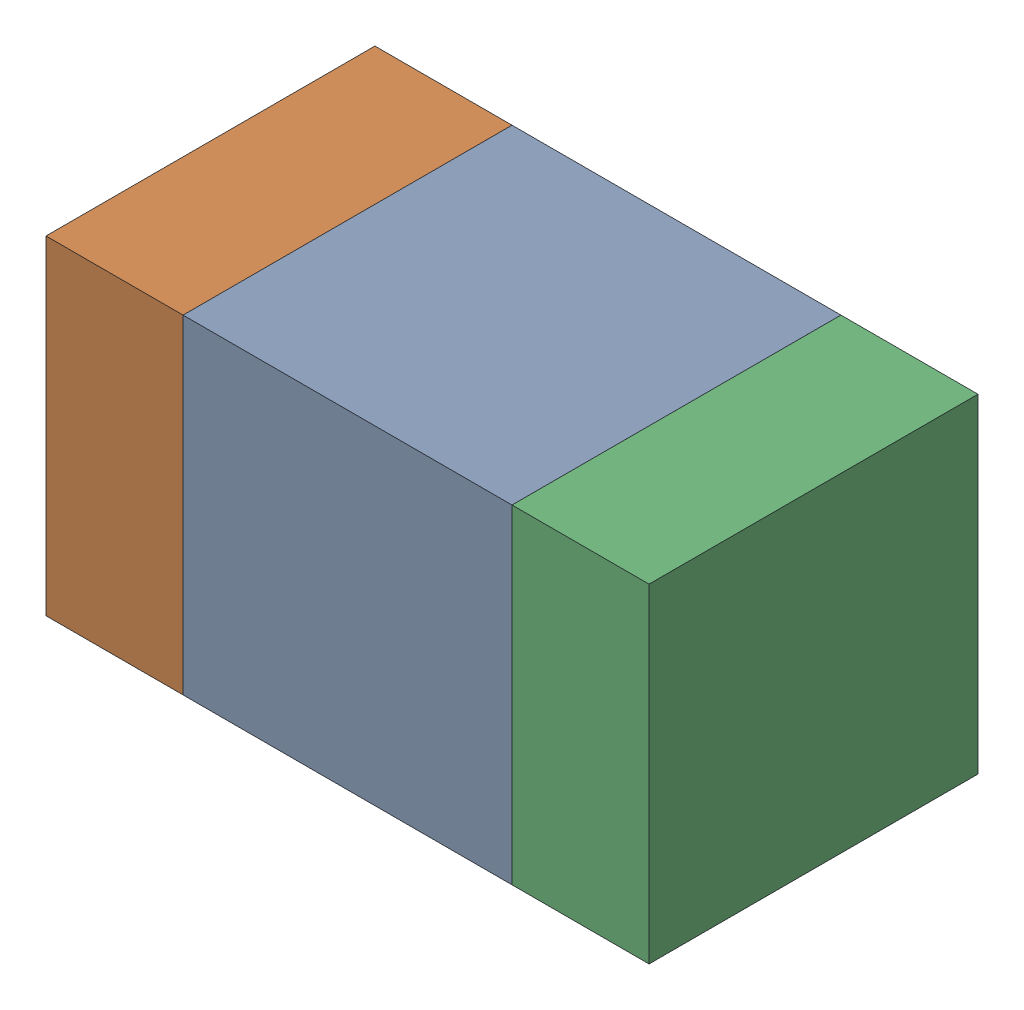
SolidWorks assembly C700PCB, configuration Default. Lengths in mm.
Overall size (1.1 0.6 0.6).
6 component instances, 2 part files, 0 mates.
Components (placement in the parent):
- 761606048-1: 761606048 [Default] at (103.7 123.3 -2.2638) size (0.6 0.6 0.6)
  - Extruded_9-1: Extruded_9 [Default] at origin size (0.6 0.6 0.6)
- 854785160-1: 854785160 [Default] at (103.275 123.3 -2.2638) size (0.25 0.6 0.6)
  - Extruded_19-1: Extruded_19 [Default] at origin size (0.25 0.6 0.6)
- 854785160-2: 854785160 [Default] at (104.125 123.3 -2.2638) size (0.25 0.6 0.6)
  - Extruded_19-1: Extruded_19 [Default] at origin size (0.25 0.6 0.6)
